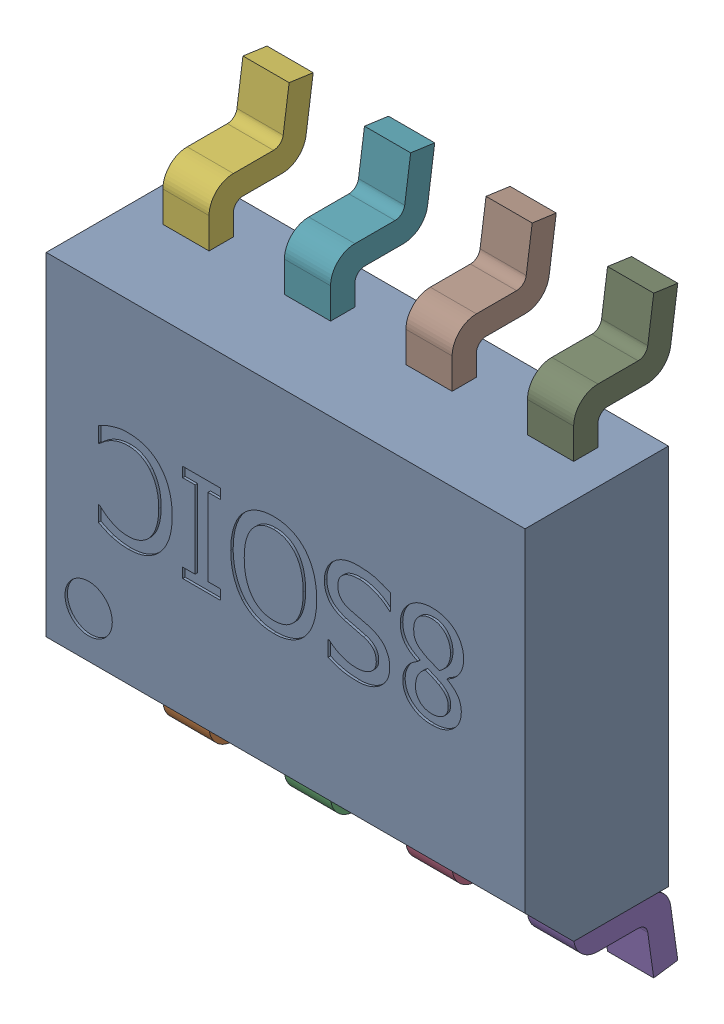
SolidWorks assembly U1.step, configuration Default. Lengths in mm.
Overall size (5 6.2 1.95).
10 component instances, 2 part files, 0 mates.
Components (placement in the parent):
- 8SIOC.step-1: 8SIOC.step [Default] at (45.4659 56.1341 0.45) x (1 0 0) z (0 -1 0) size (5 1.95 6.2)
  - 8SOIC_BODY.step-1: 8SOIC_BODY.step [Default] at origin size (5 1.5 3.99)
  - 8SOIC_PIN.step-1: 8SOIC_PIN.step [Default] at (-1.905 0.508 1.9939) x (0 0 1) z (-1 0 0) size (1.1 1.09 0.48)
  - 8SOIC_PIN.step-2: 8SOIC_PIN.step [Default] at (-0.635 0.508 1.9939) x (0 0 1) z (-1 0 0) size (1.1 1.09 0.48)
  - 8SOIC_PIN.step-3: 8SOIC_PIN.step [Default] at (0.635 0.508 1.9939) x (0 0 1) z (-1 0 0) size (1.1 1.09 0.48)
  - 8SOIC_PIN.step-4: 8SOIC_PIN.step [Default] at (1.905 0.508 1.9939) x (0 0 1) z (-1 0 0) size (1.1 1.09 0.48)
  - 8SOIC_PIN.step-5: 8SOIC_PIN.step [Default] at (-1.905 0.508 -1.9939) x (0 0 -1) z (1 0 0) size (1.1 1.09 0.48)
  - 8SOIC_PIN.step-6: 8SOIC_PIN.step [Default] at (-0.635 0.508 -1.9939) x (0 0 -1) z (1 0 0) size (1.1 1.09 0.48)
  - 8SOIC_PIN.step-7: 8SOIC_PIN.step [Default] at (0.635 0.508 -1.9939) x (0 0 -1) z (1 0 0) size (1.1 1.09 0.48)
  - 8SOIC_PIN.step-8: 8SOIC_PIN.step [Default] at (1.905 0.508 -1.9939) x (0 0 -1) z (1 0 0) size (1.1 1.09 0.48)
